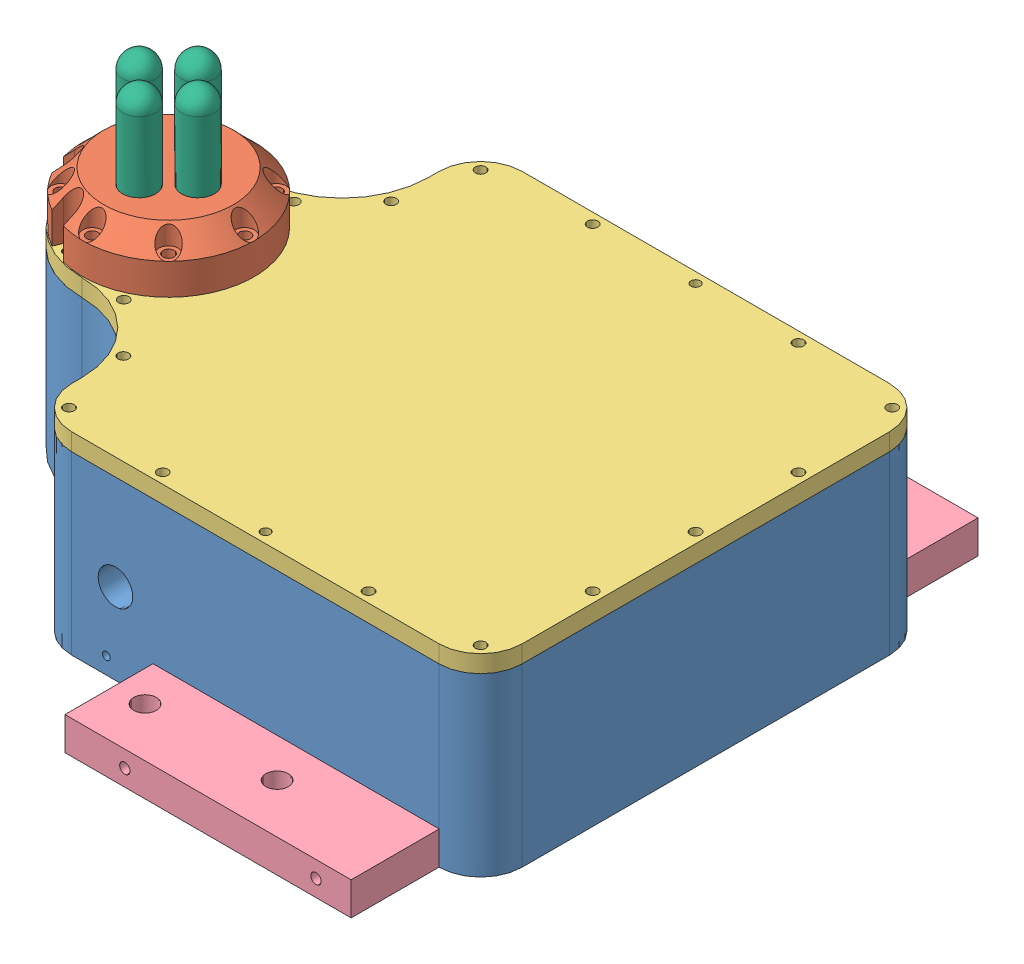
SolidWorks assembly MS-A-0009-Hydrophone Enclosure, configuration Default. Lengths in mm.
Overall size (180 95.8 180.8).
11 component instances, 6 part files, 34 mates.
Components (placement in the parent):
- MS-P-0027 Hydrophone Lid Enclosure-1: MS-P-0027 Hydrophone Lid Enclosure [Default] at (122.2031 74.6121 122.2622) size (180 50.8 130)
- MS-P-0025 Hydrophone Mount-1: MS-P-0025 Hydrophone Mount [Default] at (21.7262 132.4434 129.1283) x (0 0 -1) z (-1 0 0) size (49.59 15 49.59)
- MS-P-0026 Hydrophone Lid-1: MS-P-0026 Hydrophone Lid [Default] at (111.7262 131.4434 129.1283) x (1 0 0) z (0 0 -1) size (180 5 130)
- MS-P-0028 Hydrophone Enclosure Bracket-1: MS-P-0028 Hydrophone Enclosure Bracket [Default] at (164.7882 76.7069 38.7283) size (82.55 9.53 25.4)
- MS-P-0028 Hydrophone Enclosure Bracket-3: MS-P-0028 Hydrophone Enclosure Bracket [Default] at (164.7882 86.2319 219.5283) x (1 0 0) z (0 0 -1) size (82.55 9.53 25.4)
- Battery-1: Battery [Default] at (113.0512 80.4534 148.2158) x (0 0 -1) z (1 0 0) size (35 7 101)
- Battery-2: Battery [Default] at (113.0512 80.4534 110.0408) x (0 0 -1) z (1 0 0) size (35 7 101)
- Hydrophone-1: Hydrophone [Default] at (13.2409 147.4434 129.1283) x (-0.564928 0 -0.82514) z (-0.82514 0 0.564928) size (9.5 50 9.5)
- Hydrophone-2: Hydrophone [Default] at (21.7262 147.4434 120.643) x (0.439044 0 -0.898466) z (-0.898466 0 -0.439044) size (9.5 50 9.5)
- Hydrophone-3: Hydrophone [Default] at (30.2115 147.4434 129.1283) x (0.192579 0 0.981281) z (0.981281 0 -0.192579) size (9.5 50 9.5)
- Hydrophone-4: Hydrophone [Default] at (21.7262 147.4434 137.6135) x (-0.920994 0 -0.389576) z (-0.389576 0 0.920994) size (9.5 50 9.5)
Mates (geometry in assembly coordinates):
- Coincident1: coincident anti-aligned: plane of MS-P-0027 Hydrophone Lid Enclosure-1 through (164.7262 127.4434 76.1283) normal (0 1 0); plane of MS-P-0026 Hydrophone Lid-1 through (111.7262 127.4434 129.1283) normal (0 -1 0)
- Concentric1: concentric anti-aligned: circle of LidEnclosure-1; circle of Lid-1
- Concentric2: concentric aligned: circle of MS-P-0027 Hydrophone Lid Enclosure-1; circle of MS-P-0026 Hydrophone Lid-1
- Coincident3: coincident anti-aligned: plane of MS-P-0025 Hydrophone Mount-1 through (21.7262 132.4434 129.1283) normal (0 -1 0); plane of MS-P-0026 Hydrophone Lid-1 through (111.7262 132.4434 129.1283) normal (0 1 0)
- Concentric4: concentric aligned: circle of Mount-1; circle of Lid-1
- Coincident4: coincident anti-aligned: plane of MS-P-0027 Hydrophone Lid Enclosure-1 through (164.7262 76.6434 76.1283) normal (0 -1 0); plane of MS-P-0008-Frame, Base Plate-1 through (294.8793 76.6434 129.1283) normal (0 1 0)
- Coincident5: coincident anti-aligned: plane of MS-P-0025 Hydrophone Mount-1 through (21.7262 132.4434 129.1283) normal (0 0 -1); plane of MS-P-0008-Frame, Base Plate-1 through (294.8793 76.6434 129.1283) normal (0 0 1)
- Coincident8: coincident anti-aligned: plane of MS-P-0027 Hydrophone Lid Enclosure-1 through (164.7262 127.4434 64.1283) normal (0 0 -1); plane of MS-P-0028 Hydrophone Enclosure Bracket-1 through (164.7882 86.2319 64.1283) normal (0 0 1)
- Concentric8: concentric anti-aligned: cylinder of MS-P-0029 Raspberry Pi Mount-1 through (111.6862 121.9434 177.4533) axis (0 1 0) radius 3; cylinder of pcbWithPi-1/Raspberry Pi 3-2 through (111.6862 122.3634 177.4533) axis (0 -1 0) radius 1.375
- Concentric9: concentric anti-aligned: circle of MS-P-0029 Raspberry Pi Mount-1; circle of pcbWithPi-1/Raspberry Pi 3-2
- Coincident13: coincident: plane of MS-P-0029 Raspberry Pi Mount-1 through (136.1862 121.9434 138.4533) normal (0 -1 0); line of pcbWithPi-1/Raspberry Pi 3-2 through (108.1862 121.9434 99.0291) axis (0 0 1)
- Coincident14: coincident anti-aligned: plane of MS-P-0026 Hydrophone Lid-1 through (111.7262 127.4434 129.1283) normal (0 -1 0); plane of MS-P-0029 Raspberry Pi Mount-1 through (136.1862 127.4434 138.4533) normal (0 1 0)
- Distance3: distance = 2.54 mm anti-aligned: plane of MS-P-0029 Raspberry Pi Mount-1 through (164.1862 127.4434 180.9533) normal (1 0 0); plane of MS-P-0027 Hydrophone Lid Enclosure-1 through (166.7262 80.4534 184.1283) normal (-1 0 0)
- Distance4: distance = 3.175 mm anti-aligned: plane of MS-P-0029 Raspberry Pi Mount-1 through (108.1862 127.4434 180.9533) normal (0 0 1); plane of MS-P-0027 Hydrophone Lid Enclosure-1 through (58.7262 80.4534 184.1283) normal (0 0 -1)
- Concentric10: concentric anti-aligned: unknown of MS-P-0027 Hydrophone Lid Enclosure-1; cylinder of MS-P-0028 Hydrophone Enclosure Bracket-3 through (99.5102 81.4694 219.5283) axis (0 0 -1) radius 1.5
- Distance5: distance = 3.175 mm anti-aligned: plane of Battery-2 through (163.5512 87.4534 127.5408) normal (0 0 1); plane of Battery-1 through (163.5512 87.4534 130.7158) normal (0 0 -1)
- Coincident16: coincident aligned: plane of Battery-1 through (62.5512 87.4534 130.7158) normal (-1 0 0); plane of Battery-2 through (62.5512 87.4534 92.5408) normal (-1 0 0)
- Coincident17: coincident aligned: plane of Battery-1 through (113.0512 80.4534 148.2158) normal (0 -1 0); plane of Battery-2 through (113.0512 80.4534 110.0408) normal (0 -1 0)
- Width1: width anti-aligned: plane of Battery-2 through (163.5512 87.4534 92.5408) normal (0 0 -1); plane of Battery-1 through (163.5512 87.4534 165.7158) normal (0 0 1); plane of MS-P-0027 Hydrophone Lid Enclosure-1 through (166.7262 80.4534 74.1283) normal (0 0 1); plane of MS-P-0027 Hydrophone Lid Enclosure-1 through (58.7262 80.4534 184.1283) normal (0 0 -1)
- Coincident18: coincident anti-aligned: plane of MS-P-0027 Hydrophone Lid Enclosure-1 through (21.7262 80.4534 179.1283) normal (0 1 0); plane of Battery-2 through (113.0512 80.4534 110.0408) normal (0 -1 0)
- Distance6: distance = 3.175 mm anti-aligned: plane of Battery-1 through (163.5512 87.4534 130.7158) normal (1 0 0); plane of MS-P-0027 Hydrophone Lid Enclosure-1 through (166.7262 80.4534 184.1283) normal (-1 0 0)
- Coincident19: coincident aligned: circle of MS-P-0025 Hydrophone Mount-1; cylinder of Hydrophone-1 through (13.2409 172.4434 129.1283) axis (0 1 0) radius 3.5
- Concentric11: concentric aligned: cylinder of MS-P-0025 Hydrophone Mount-1 through (43.7262 147.4434 129.1283) axis (0 1 0) radius 1.632; circle of MS-P-0026 Hydrophone Lid-1
- Concentric13: concentric aligned: cylinder of MS-P-0025 Hydrophone Mount-1 through (21.7262 132.4434 120.643) axis (0 1 0) radius 3.5; cylinder of Hydrophone-2 through (21.7262 172.4434 120.643) axis (0 1 0) radius 3.5
- Coincident20: coincident aligned: circle of MS-P-0025 Hydrophone Mount-1; cylinder of Hydrophone-3 through (30.2115 172.4434 129.1283) axis (0 1 0) radius 3.5
- Coincident21: coincident anti-aligned: plane of MS-P-0025 Hydrophone Mount-1 through (21.7262 147.4434 129.1283) normal (0 1 0); plane of Hydrophone-1 through (16.1289 147.4434 127.151) normal (0 -1 0)
- Coincident22: coincident anti-aligned: plane of MS-P-0025 Hydrophone Mount-1 through (21.7262 147.4434 129.1283) normal (0 1 0); plane of Hydrophone-3 through (26.777 147.4434 129.8023) normal (0 -1 0)
- Coincident23: coincident anti-aligned: plane of MS-P-0025 Hydrophone Mount-1 through (21.7262 147.4434 129.1283) normal (0 1 0); plane of Hydrophone-2 through (24.8708 147.4434 122.1796) normal (0 -1 0)
- Coincident24: coincident anti-aligned: plane of MS-P-0025 Hydrophone Mount-1 through (21.7262 147.4434 129.1283) normal (0 1 0); plane of Hydrophone-4 through (23.0897 147.4434 134.3901) normal (0 -1 0)
- Concentric15: concentric anti-aligned: circle of MS-P-0025 Hydrophone Mount-1; cylinder of Hydrophone-4 through (21.7262 172.4434 137.6135) axis (0 1 0) radius 4.75
- Parallel1: parallel: plane of assembly; plane of assembly; plane of MS-P-0027 Hydrophone Lid Enclosure-1 through (21.7262 80.4534 179.1283) normal (0 1 0); plane of Daq Rev3.step-1/Board.step-1/Open CASCADE STEP translator 6.8 1.1.1.step-1 through (160.3762 124.2684 163.4183) normal (0 1 0); plane of assembly; plane of assembly; plane of assembly; plane of assembly; plane of ?; plane of ?; plane of ?; plane of ?; plane of assembly; plane of assembly; plane of ?; plane of ?; plane of assembly; plane of assembly; plane of ?; plane of ?
- Width2: width: plane of MS-P-0027 Hydrophone Lid Enclosure-1 through (58.7262 80.4534 184.1283) normal (0 0 -1); plane of MS-P-0027 Hydrophone Lid Enclosure-1 through (166.7262 80.4534 74.1283) normal (0 0 1); plane of Daq Rev3.step-1/Board.step-1/Open CASCADE STEP translator 6.8 1.1.1.step-1 through (160.3762 124.2684 163.4183) normal (0 0 1); plane of Daq Rev3.step-1/Board.step-1/Open CASCADE STEP translator 6.8 1.1.1.step-1 through (75.2862 124.2684 94.8382) normal (0 0 -1)
- Distance7: distance = 6.35 mm: plane of Daq Rev3.step-1/Board.step-1/Open CASCADE STEP translator 6.8 1.1.1.step-1 through (160.3762 124.2684 94.8382) normal (1 0 0); plane of MS-P-0027 Hydrophone Lid Enclosure-1 through (166.7262 80.4534 184.1283) normal (-1 0 0)
- Distance8: distance = 3.175 mm aligned: plane of Daq Rev3.step-1/Board.step-1/Open CASCADE STEP translator 6.8 1.1.1.step-1 through (160.3762 124.2684 163.4183) normal (0 1 0); plane of MS-P-0027 Hydrophone Lid Enclosure-1 through (164.7262 127.4434 76.1283) normal (0 1 0)
